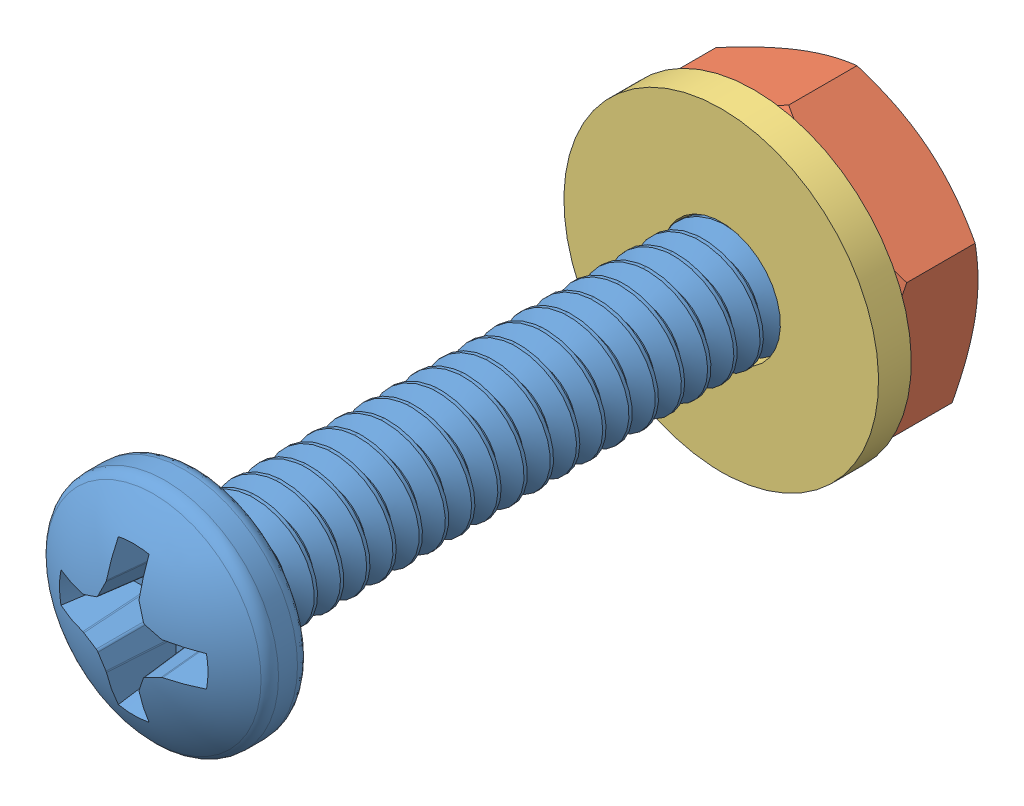
SolidWorks assembly 6-32 x 0.75in Screw Assy, configuration Default. Lengths in mm.
Overall size (9.53 10.26 22.27).
3 component instances, 3 part files, 5 mates.
Components (placement in the parent):
- 6-32 x 0.75in Screw-1: 6-32 x 0.75in Screw [90234A215] at origin size (6.86 6.86 21.56)
- 6-32 Nut-1: 6-32 Nut [90545A007] at (0 0 0.8603) x (0.988403 -0.151855 0) z (-0.151855 -0.988403 0) size (7.94 3.39 9.17)
- 6-32 Washer-1: 6-32 Washer [96765A115] at (0 0 3.24) x (-1 0 0) z (0 -1 0) size (9.53 0.99 9.53)
Mates (geometry in assembly coordinates):
- Concentric1: concentric: circle of 6-32 x 0.75in Screw-1; circle of 6-32 Washer-1
- Coincident1: coincident: line of 6-32 x 0.75in Screw-1 through (0 0 22.7072) axis (0 0 -1); line of 6-32 Nut-1 through (0 0 -1.0119) axis (0 0 1)
- Screw1: screw = 1: line of 6-32 x 0.75in Screw-1 through (0 0 22.7072) axis (0 0 -1); line of 6-32 Nut-1 through (0 0 -1.0119) axis (0 0 1)
- Coincident2: coincident: plane of 6-32 Nut-1 through (-3.5748 2.8675 2.2494) normal (0 0 1); plane of 6-32 Washer-1 through (0 0 2.2494) normal (0 0 -1)
- Distance3: distance = 15.81 mm: plane of 6-32 x 0.75in Screw-1 through (0 0 19.05) normal (0 0 -1); plane of 6-32 Washer-1 through (0 0 3.24) normal (0 0 1)
